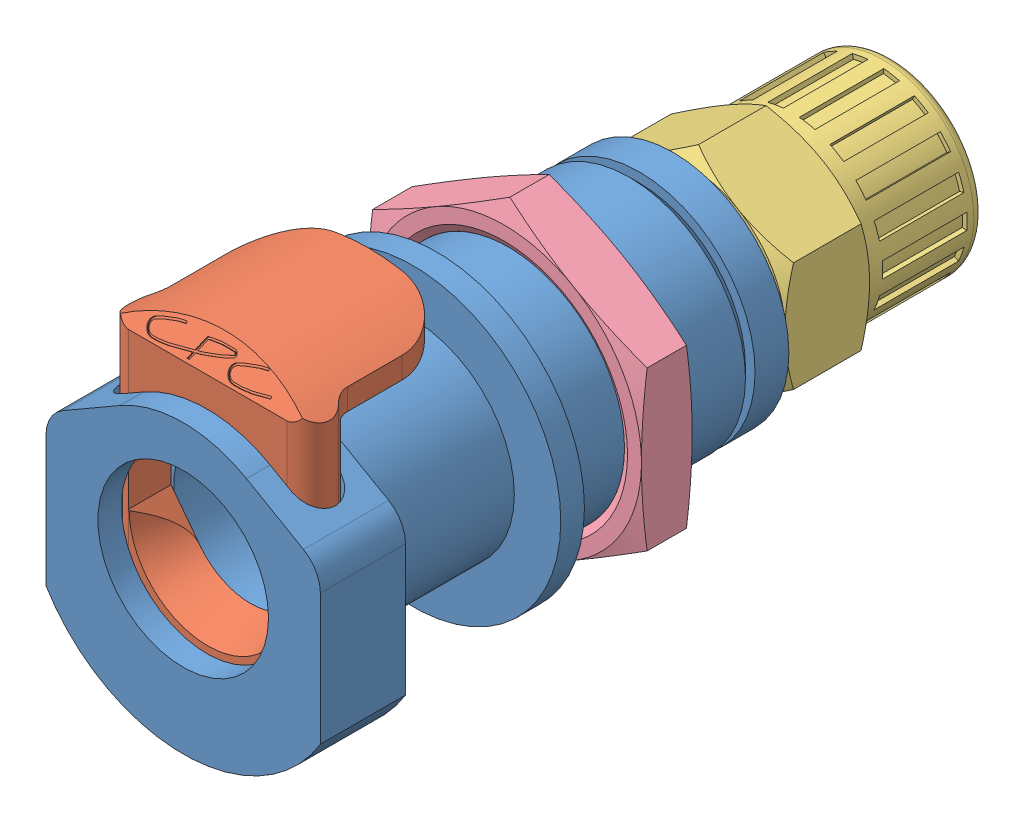
SolidWorks assembly apc12006_6_0, configuration По умолчанию. Lengths in mm.
Overall size (22.23 26 53.34).
4 component instances, 4 part files, 5 mates.
Components (placement in the parent):
- APC12006-BODY-1: APC12006-BODY [По умолчанию] at origin size (22.23 23.18 53.34)
- APC-LATCH_3-1: APC-LATCH_3 [По умолчанию] at (0 -0.0327 -0.0762) size (15.11 23.5 12.49)
- 108900-1: 108900 [По умолчанию] at origin size (14.29 16.5 15.24)
- 120701-1: 120701 [По умолчанию] at origin size (20.64 23.83 3.81)
Mates (geometry in assembly coordinates):
- Концентричный1: concentric anti-aligned: cylinder of APC12006-BODY-1 through (0 0 -26.2922) axis (0 0 1) radius 8.7312; circle of 120701-1
- Концентричный2: concentric aligned: cylinder of APC12006-BODY-1 through (0 0 -41.6395) axis (0 0 1) radius 6.35; cylinder of 108900-1 through (0 0 -48.514) axis (0 0 1) radius 6.858
- Ширина1: width anti-aligned: plane of APC-LATCH_3-1 through (0 -0.0327 -1.8542) normal (0 0 1); plane of APC-LATCH_3-1 through (0 -0.0327 -5.0546) normal (0 0 -1); plane of APC12006-BODY-1 through (-6.3246 14.2875 -1.778) normal (0 0 -1); plane of APC12006-BODY-1 through (6.3246 14.2875 -5.1308) normal (0 0 1)
- Совпадение1: coincident aligned: plane of APC12006-BODY-1 through (0 0 0) normal (1 0 0); plane of APC-LATCH_3-1 through (0 -0.0327 -0.0762) normal (1 0 0)
- Совпадение2: coordinate: point of ?
